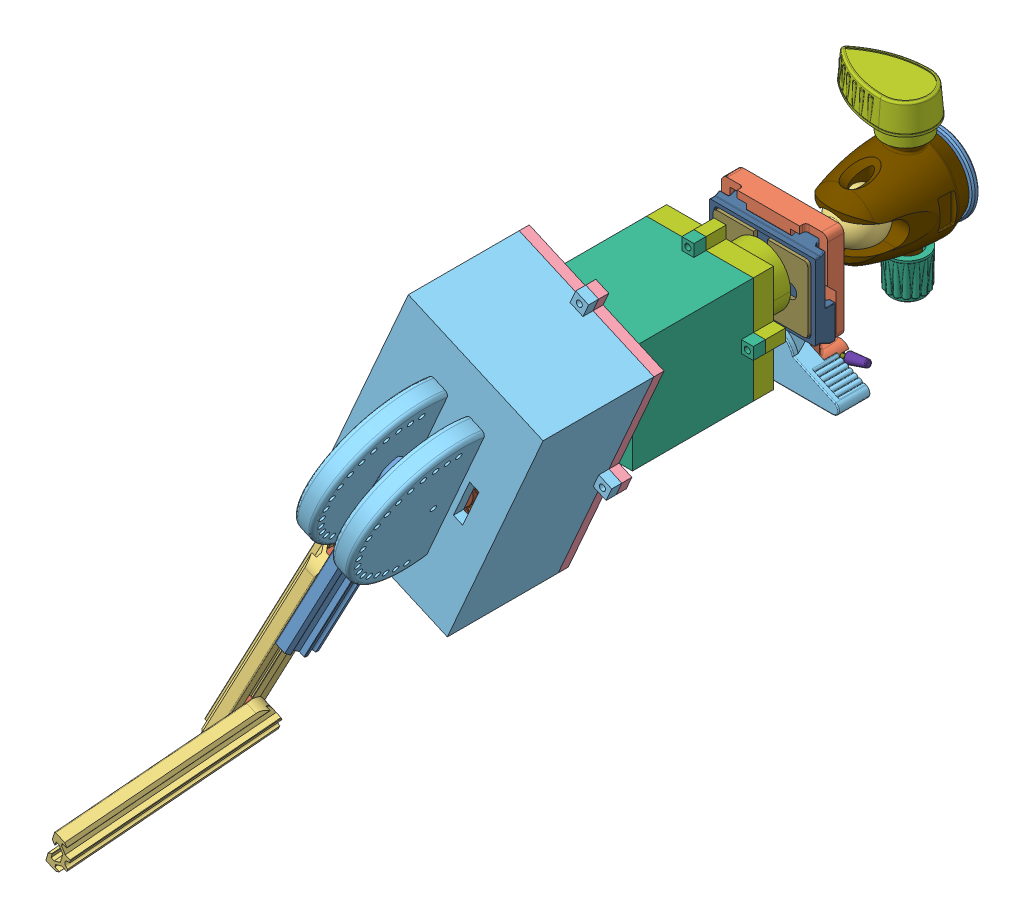
SolidWorks assembly Ensamblaje_modelo1, configuration Predeterminado. Lengths in mm.
Overall size (138.43 225.18 378.64).
164 component instances, 151 part files, 39 mates.
Components (placement in the parent):
- Brazo_10cm_aluminnino-1: Brazo_10cm_aluminnino [Predeterminado] at (-448.8005 -805.3039 -5.9199) x (0.069335 0.157727 0.985046) z (-0.915454 0.402424 0) size (20 100 10.12)
- Deslizador-3: Deslizador [Predeterminado] at (-316.6339 -504.6447 -43.0612) x (0.069335 0.157727 0.985046) z (0.396406 0.901764 -0.172294) size (11 6.1 10)
- Brazo2_10cm_aluminnino-3: Brazo2_10cm_aluminnino [Predeterminado] at (-469.25 -851.8237 23.2719) x (-0.069335 -0.157727 -0.985046) z (0.915454 -0.402424 0) size (20 100 10.12)
- Deslizador-4: Deslizador [Predeterminado] at (-312.6698 -495.6271 -44.7841) x (0.069335 0.157727 0.985046) z (-0.396406 -0.901764 0.172294) size (11 6.1 10)
- Deslizador-5: Deslizador [Predeterminado] at (-349.733 -579.9403 -48.9786) x (-0.069335 -0.157727 -0.985046) z (0.396406 0.901764 -0.172294) size (11 6.1 10)
- Brazo2_10cm_aluminnino-4: Brazo2_10cm_aluminnino [Predeterminado] at (-378.3724 -645.0906 342.2993) x (0.396265 0.901444 0.174278) z (-0.915454 0.402424 0) size (20 100 10.12)
- Deslizador-6: Deslizador [Predeterminado] at (-350.6696 -582.071 -46.6558) x (-0.396265 -0.901444 -0.174278) z (-0.070134 -0.159543 0.984696) size (11 6.1 10)
- Base_electronica-1: Base_electronica [Predeterminado] at (-294.7034 -471.5152 -134.264) x (0.402424 0.915454 0) z (0 0 -1) size (132 87 23)
- Carcaza_electronica-2: Carcaza_electronica [Predeterminado] at (-297.1955 -448.8025 -29.264) x (-0.402424 -0.915454 0) z (0 0 -1) size (132 87 104.68)
- Soporte_motor_superior-1: Soporte_motor_superior [Predeterminado] at (-288.9316 -454.051 -209.264) size (65 65 60)
- motor_abajo_acople-1: motor_abajo_acople [Predeterminado] at (-288.9316 -454.051 -209.264) x (0 1 0) z (0 0 -1) size (65 65 30)
- Manfrotto - 494RC2 Head Assy-1: Manfrotto - 494RC2 Head Assy [Predeterminado] at (-288.9316 -453.3297 -286.264) x (0 1 0) z (1 0 0) size (91.96 94.5 69.28)
  - Manfrotto - 494RC2 Head Assy.stp-1: Manfrotto - 494RC2 Head Assy.stp [Predeterminado] at origin size (91.96 94.5 69.28)
    - Quick Release Assy.stp-1: Quick Release Assy.stp [Predeterminado] at (-0.7213 41 0) x (-1 0 0) z (0 0 -1) size (42.4 16.85 52.52)
      - Thumb Screw Assy.stp-1: Thumb Screw Assy.stp [Predeterminado] at (0 -1.5 0) x (0 0 -1) z (-1 0 0) size (29.5 16 20.75)
        - Thumb Screw.stp-1: Thumb Screw.stp [Predeterminado] at origin size (15.01 16 15)
        - Thumb Screw Handle.stp-1: Thumb Screw Handle.stp [Predeterminado] at (0 1 0) size (29.5 2.5 14.5)
      - Quick Release Mounting.stp-1: Quick Release Mounting.stp [Predeterminado] at origin size (42.4 10.35 52.52)
      - IS 3075-3 3.2.stp-1: IS 3075-3 3.2.stp [Predeterminado] at (0 3.5 -1.9764) x (1 0 0) z (0 1 0) size (7.3 6.15 0.6)
      - Quick Release Rubber Pad.stp-1: Quick Release Rubber Pad.stp [Predeterminado] at (0 5 0) x (-1 0 0) z (0 0 -1) size (33 2 47)
    - Manfrotto Logo 01.stp-1: Manfrotto Logo 01.stp [Predeterminado] at (0 -22 -19) x (-1 0 0) z (0 -1 0) size (8.5 1.8 8.5)
      - Manfrotto Logo 01 - 1.stp-1: Manfrotto Logo 01 - 1.stp [Predeterminado] at origin size (8.5 0.3 8.5)
      - Manfrotto Logo 01 - 2.stp-1: Manfrotto Logo 01 - 2.stp [Predeterminado] at (0 1.05 0) x (0 0 1) z (-1 0 0) size (8.5 1.5 8.5)
    - Locking Pin Assy.stp-1: Locking Pin Assy.stp [Predeterminado] at (-40.5 28.5 12.6) x (0.97437 0 -0.224951) z (0.224951 0 0.97437) size (7 17 21)
      - Locking Pin.stp-1: Locking Pin.stp [Predeterminado] at origin size (7 17 7)
      - Locking Pin Lever.stp-1: Locking Pin Lever.stp [Predeterminado] at (0 -5.5 6) x (1 0 0) z (0 1 0) size (2 17 2)
      - Locking Pin Lever Rubber.stp-1: Locking Pin Lever Rubber.stp [Predeterminado] at (0 -5.5 12.5) size (4.96 4.96 10)
    - Base Casting.stp-1: Base Casting.stp [Predeterminado] at origin size (64 51.03 43.02)
    - Base Plate.stp-1: Base Plate.stp [Predeterminado] at (0 -40.5 0) size (39.5 19 39.5)
    - Mount Casting.stp-1: Mount Casting.stp [Predeterminado] at (0 36 0) size (71.96 24.08 53.67)
    - Ball Joint.stp-1: Ball Joint.stp [Predeterminado] at (0 -1 0) size (25 40.5 25)
    - ISO 10642 M5 x  16.stp-1: ISO 10642 M5 x  16.stp [Predeterminado] at (0 34.6 0) x (0 -1 0) z (0 0 1) size (16 9.43 9.43)
    - Quick Release Catch.stp-1: Quick Release Catch.stp [Predeterminado] at (-34 40.5 -0.9) size (25 15.5 49)
    - Friction Knob.stp-1: Friction Knob.stp [Predeterminado] at (-25 -26 0) x (0 1 0) z (0 0 1) size (19.07 19 19.04)
    - Locking Knob.stp-1: Locking Knob.stp [Predeterminado] at (31.5 -25 0) x (0 1 0) z (0 0 -1) size (27.31 20.5 46)
- NEMA17 17HS8401.step-4: NEMA17 17HS8401.step [Predeterminado] at (-288.9316 -454.051 -154.264) x (-1 0 0) z (0 -1 0) size (42 72.35 47.08)
- Raspberry-1: Raspberry [Predeterminado] at (-301.1009 -413.7462 -103.764) x (-0.402424 -0.915454 0) z (0 0 1) size (88 57 24.1)
  - full raspberry pi 4 upgrade cooling.step-1: full raspberry pi 4 upgrade cooling.step [Predeterminado] at origin size (88 57 24.1)
    - радиатор верх.step-1: радиатор верх.step [Predeterminado] at (70 0 7.1) size (70 56 15)
    - радиатор низ.step-1: радиатор низ.step [Predeterminado] at (0 0 -2.5) x (0 1 0) z (0 0 -1) size (56 87 7.5)
    - вентилятор.step-1: вентилятор.step [Predeterminado] at (46.1053 34.1447 9.6) x (0 -1 0) z (0 0 -1) size (25 25 6)
    - вентилятор.step-2: вентилятор.step [Predeterminado] at (21.1053 34.1447 9.6) x (0 -1 0) z (0 0 -1) size (25 25 6)
    - распбери 4.step-1: распбери 4.step [Predeterminado] at origin size (85 56 1.6)
    - распбери 4-0.step-1: распбери 4-0.step [Predeterminado] at origin size (2.5 5 2.4)
    - распбери 4-1.step-1: распбери 4-1.step [Predeterminado] at origin size (2.5 5 2.4)
    - распбери 4-2.step-1: распбери 4-2.step [Predeterminado] at origin size (2.5 5 2.4)
    - распбери 4-3.step-1: распбери 4-3.step [Predeterminado] at origin size (2.5 5 2.4)
    - распбери 4-4.step-1: распбери 4-4.step [Predeterminado] at origin size (2.5 5 2.4)
    - распбери 4-5.step-1: распбери 4-5.step [Predeterminado] at origin size (2.5 5 2.4)
    - распбери 4-6.step-1: распбери 4-6.step [Predeterminado] at origin size (2.5 5 2.4)
    - распбери 4-7.step-1: распбери 4-7.step [Predeterminado] at origin size (2.5 5 2.4)
    - распбери 4-8.step-1: распбери 4-8.step [Predeterminado] at origin size (2.5 5 2.4)
    - распбери 4-9.step-1: распбери 4-9.step [Predeterminado] at origin size (2.5 5 2.4)
    - распбери 4-10.step-1: распбери 4-10.step [Predeterminado] at origin size (2.5 5 2.4)
    - распбери 4-11.step-1: распбери 4-11.step [Predeterminado] at origin size (2.5 5 2.4)
    - распбери 4-12.step-1: распбери 4-12.step [Predeterminado] at origin size (2.5 5 2.4)
    - распбери 4-13.step-1: распбери 4-13.step [Predeterminado] at origin size (2.5 5 2.4)
    - распбери 4-14.step-1: распбери 4-14.step [Predeterminado] at origin size (2.5 5 2.4)
    - распбери 4-15.step-1: распбери 4-15.step [Predeterminado] at origin size (2.5 5 2.4)
    - распбери 4-16.step-1: распбери 4-16.step [Predeterminado] at origin size (2.5 5 2.4)
    - распбери 4-17.step-1: распбери 4-17.step [Predeterminado] at origin size (2.5 5 2.4)
    - распбери 4-18.step-1: распбери 4-18.step [Predeterminado] at origin size (2.5 5 2.4)
    - распбери 4-19.step-1: распбери 4-19.step [Predeterminado] at origin size (2.5 5 2.4)
    - распбери 4-20.step-1: распбери 4-20.step [Predeterminado] at origin size (2.5 2.5 2.4)
    - распбери 4-21.step-1: распбери 4-21.step [Predeterminado] at origin size (2.5 2.5 2.4)
    - распбери 4-22.step-1: распбери 4-22.step [Predeterminado] at origin size (2.5 2.5 2.4)
    - распбери 4-23.step-1: распбери 4-23.step [Predeterminado] at origin size (2.5 2.5 2.4)
    - распбери 4-24.step-1: распбери 4-24.step [Predeterminado] at origin size (0.65 0.65 11.5)
    - распбери 4-25.step-1: распбери 4-25.step [Predeterminado] at origin size (0.65 0.65 11.5)
    - распбери 4-26.step-1: распбери 4-26.step [Predeterminado] at origin size (0.65 0.65 11.5)
    - распбери 4-27.step-1: распбери 4-27.step [Predeterminado] at origin size (0.65 0.65 11.5)
    - распбери 4-28.step-1: распбери 4-28.step [Predeterminado] at origin size (0.65 0.65 11.5)
    - распбери 4-29.step-1: распбери 4-29.step [Predeterminado] at origin size (0.65 0.65 11.5)
    - распбери 4-30.step-1: распбери 4-30.step [Predeterminado] at origin size (0.65 0.65 11.5)
    - распбери 4-31.step-1: распбери 4-31.step [Predeterminado] at origin size (0.65 0.65 11.5)
    - распбери 4-32.step-1: распбери 4-32.step [Predeterminado] at origin size (0.65 0.65 11.5)
    - распбери 4-33.step-1: распбери 4-33.step [Predeterminado] at origin size (0.65 0.65 11.5)
    - распбери 4-34.step-1: распбери 4-34.step [Predeterminado] at origin size (0.65 0.65 11.5)
    - распбери 4-35.step-1: распбери 4-35.step [Predeterminado] at origin size (0.65 0.65 11.5)
    - распбери 4-36.step-1: распбери 4-36.step [Predeterminado] at origin size (0.65 0.65 11.5)
    - распбери 4-37.step-1: распбери 4-37.step [Predeterminado] at origin size (0.65 0.65 11.5)
    - распбери 4-38.step-1: распбери 4-38.step [Predeterminado] at origin size (0.65 0.65 11.5)
    - распбери 4-39.step-1: распбери 4-39.step [Predeterminado] at origin size (0.65 0.65 11.5)
    - распбери 4-40.step-1: распбери 4-40.step [Predeterminado] at origin size (0.65 0.65 11.5)
    - распбери 4-41.step-1: распбери 4-41.step [Predeterminado] at origin size (0.65 0.65 11.5)
    - распбери 4-42.step-1: распбери 4-42.step [Predeterminado] at origin size (0.65 0.65 11.5)
    - распбери 4-43.step-1: распбери 4-43.step [Predeterminado] at origin size (0.65 0.65 11.5)
    - распбери 4-44.step-1: распбери 4-44.step [Predeterminado] at origin size (0.65 0.65 11.5)
    - распбери 4-45.step-1: распбери 4-45.step [Predeterminado] at origin size (0.65 0.65 11.5)
    - распбери 4-46.step-1: распбери 4-46.step [Predeterminado] at origin size (0.65 0.65 11.5)
    - распбери 4-47.step-1: распбери 4-47.step [Predeterminado] at origin size (0.65 0.65 11.5)
    - распбери 4-48.step-1: распбери 4-48.step [Predeterminado] at origin size (0.65 0.65 11.5)
    - распбери 4-49.step-1: распбери 4-49.step [Predeterminado] at origin size (0.65 0.65 11.5)
    - распбери 4-50.step-1: распбери 4-50.step [Predeterminado] at origin size (0.65 0.65 11.5)
    - распбери 4-51.step-1: распбери 4-51.step [Predeterminado] at origin size (0.65 0.65 11.5)
    - распбери 4-52.step-1: распбери 4-52.step [Predeterminado] at origin size (0.65 0.65 11.5)
    - распбери 4-53.step-1: распбери 4-53.step [Predeterminado] at origin size (0.65 0.65 11.5)
    - распбери 4-54.step-1: распбери 4-54.step [Predeterminado] at origin size (0.65 0.65 11.5)
    - распбери 4-55.step-1: распбери 4-55.step [Predeterminado] at origin size (0.65 0.65 11.5)
    - распбери 4-56.step-1: распбери 4-56.step [Predeterminado] at origin size (0.65 0.65 11.5)
    - распбери 4-57.step-1: распбери 4-57.step [Predeterminado] at origin size (0.65 0.65 11.5)
    - распбери 4-58.step-1: распбери 4-58.step [Predeterminado] at origin size (0.65 0.65 11.5)
    - распбери 4-59.step-1: распбери 4-59.step [Predeterminado] at origin size (0.65 0.65 11.5)
    - распбери 4-60.step-1: распбери 4-60.step [Predeterminado] at origin size (0.65 0.65 11.5)
    - распбери 4-61.step-1: распбери 4-61.step [Predeterminado] at origin size (0.65 0.65 11.5)
    - распбери 4-62.step-1: распбери 4-62.step [Predeterminado] at origin size (0.65 0.65 11.5)
    - распбери 4-63.step-1: распбери 4-63.step [Predeterminado] at origin size (0.65 0.65 11.5)
    - распбери 4-64.step-1: распбери 4-64.step [Predeterminado] at origin size (0.65 0.65 11.5)
    - распбери 4-65.step-1: распбери 4-65.step [Predeterminado] at origin size (0.65 0.65 11.5)
    - распбери 4-66.step-1: распбери 4-66.step [Predeterminado] at origin size (0.65 0.65 11.5)
    - распбери 4-67.step-1: распбери 4-67.step [Predeterminado] at origin size (0.65 0.65 11.5)
    - распбери 4-68.step-1: распбери 4-68.step [Predeterminado] at origin size (0.8 14 5)
    - распбери 4-69.step-1: распбери 4-69.step [Predeterminado] at origin size (2.5 20 5)
    - распбери 4-70.step-1: распбери 4-70.step [Predeterminado] at origin size (2.5 20 5)
    - распбери 4-71.step-1: распбери 4-71.step [Predeterminado] at origin size (0.8 14 5)
    - распбери 4-72.step-1: распбери 4-72.step [Predeterminado] at origin size (11 13 2)
    - распбери 4-73.step-1: распбери 4-73.step [Predeterminado] at origin size (15 15 2.5)
    - распбери 4-74.step-1: распбери 4-74.step [Predeterminado] at origin size (10 15 1)
    - распбери 4-75.step-1: распбери 4-75.step [Predeterminado] at origin size (8 8 1)
    - распбери 4-76.step-1: распбери 4-76.step [Predeterminado] at origin size (6 6 1)
    - распбери 4-77.step-1: распбери 4-77.step [Predeterminado] at origin size (4.5 7 2)
    - распбери 4-78.step-1: распбери 4-78.step [Predeterminado] at origin size (9 7 3)
    - распбери 4-79.step-1: распбери 4-79.step [Predeterminado] at origin size (6.5 7 3)
    - распбери 4-80.step-1: распбери 4-80.step [Predeterminado] at origin size (6.5 7 3)
    - распбери 4-81.step-1: распбери 4-81.step [Predeterminado] at origin size (6.5 0.5 3)
    - распбери 4-82.step-1: распбери 4-82.step [Predeterminado] at origin size (7 12.5 6)
    - распбери 4-83.step-1: распбери 4-83.step [Predeterminado] at origin size (6 1 6)
    - распбери 4-84.step-1: распбери 4-84.step [Predeterminado] at origin size (18 13 15)
    - распбери 4-85.step-1: распбери 4-85.step [Predeterminado] at origin size (9 10 1)
    - распбери 4-86.step-1: распбери 4-86.step [Predeterminado] at origin size (9 10 1)
    - распбери 4-87.step-1: распбери 4-87.step [Predeterminado] at origin size (9 10 1)
    - распбери 4-88.step-1: распбери 4-88.step [Predeterminado] at origin size (9 12 9.5)
    - распбери 4-89.step-1: распбери 4-89.step [Predeterminado] at origin size (9 10 1)
    - распбери 4-90.step-1: распбери 4-90.step [Predeterminado] at origin size (3 2.6 1.5)
    - распбери 4-91.step-1: распбери 4-91.step [Predeterminado] at origin size (3 2.6 1.5)
    - распбери 4-92.step-1: распбери 4-92.step [Predeterminado] at origin size (6 2.6 1.5)
    - распбери 4-93.step-1: распбери 4-93.step [Predeterminado] at origin size (6 2.6 1.5)
    - распбери 4-94.step-1: распбери 4-94.step [Predeterminado] at origin size (18 16 13.5)
    - распбери 4-95.step-1: распбери 4-95.step [Predeterminado] at origin size (8 12.2 5.1)
    - распбери 4-96.step-1: распбери 4-96.step [Predeterminado] at origin size (7 1.2 0.6)
    - распбери 4-97.step-1: распбери 4-97.step [Predeterminado] at origin size (7 1.2 0.6)
    - распбери 4-98.step-1: распбери 4-98.step [Predeterminado] at origin size (7 1.2 0.6)
    - распбери 4-99.step-1: распбери 4-99.step [Predeterminado] at origin size (7 1.2 0.6)
    - распбери 4-100.step-1: распбери 4-100.step [Predeterminado] at origin size (7 1.2 0.6)
    - распбери 4-101.step-1: распбери 4-101.step [Predeterminado] at origin size (7 1.2 0.6)
    - распбери 4-102.step-1: распбери 4-102.step [Predeterminado] at origin size (7 1.2 0.6)
    - распбери 4-103.step-1: распбери 4-103.step [Predeterminado] at origin size (7 1.2 0.6)
    - распбери 4-104.step-1: распбери 4-104.step [Predeterminado] at origin size (7 1.2 0.6)
    - распбери 4-105.step-1: распбери 4-105.step [Predeterminado] at origin size (7 1.2 0.6)
    - распбери 4-106.step-1: распбери 4-106.step [Predeterminado] at origin size (7 1.2 0.6)
    - распбери 4-107.step-1: распбери 4-107.step [Predeterminado] at origin size (18 13 15)
    - распбери 4-108.step-1: распбери 4-108.step [Predeterminado] at origin size (7 1.2 0.6)
    - распбери 4-109.step-1: распбери 4-109.step [Predeterminado] at origin size (13 11 1)
    - распбери 4-110.step-1: распбери 4-110.step [Predeterminado] at origin size (13 11 1)
    - распбери 4-111.step-1: распбери 4-111.step [Predeterminado] at origin size (7 0.6 0.2)
    - распбери 4-112.step-1: распбери 4-112.step [Predeterminado] at origin size (7 0.6 0.2)
    - распбери 4-113.step-1: распбери 4-113.step [Predeterminado] at origin size (7 0.6 0.2)
    - распбери 4-114.step-1: распбери 4-114.step [Predeterminado] at origin size (7 0.6 0.2)
    - распбери 4-115.step-1: распбери 4-115.step [Predeterminado] at origin size (7 0.6 0.2)
    - распбери 4-116.step-1: распбери 4-116.step [Predeterminado] at origin size (7 0.6 0.2)
    - распбери 4-117.step-1: распбери 4-117.step [Predeterminado] at origin size (7 0.6 0.2)
    - распбери 4-118.step-1: распбери 4-118.step [Predeterminado] at origin size (7 0.6 0.2)
    - распбери 4-119.step-1: распбери 4-119.step [Predeterminado] at origin size (8.63 10.92 0.05)
    - распбери 4-120.step-1: распбери 4-120.step [Predeterminado] at origin size (11 12 1.4)
Mates (geometry in assembly coordinates):
- Coincidente29: coincident anti-aligned: plane of Brazo_10cm_aluminnino-1 through (-288.279 -444.6129 -70.4047) normal (0.069335 0.157727 0.985046); plane of Deslizador-3 through (-310.5959 -499.4559 -60.0523) normal (-0.069335 -0.157727 -0.985046)
- Coincidente31: coincident anti-aligned: plane of Brazo_10cm_aluminnino-1 through (-283.9438 -445.4364 -64.7407) normal (-0.915454 0.402424 0); plane of Deslizador-3 through (-307.7622 -499.6194 -54.3883) normal (0.915454 -0.402424 0)
- Coincidente33: coincident anti-aligned: plane of Brazo_10cm_aluminnino-1 through (-289.8624 -443.7437 -69.4985) normal (-0.915454 0.402424 0); plane of Brazo2_10cm_aluminnino-3 through (-311.6987 -493.4179 -60.0075) normal (0.915454 -0.402424 0)
- Coincidente34: coincident aligned: plane of Brazo_10cm_aluminnino-1 through (-285.2764 -446.7797 -74.8374) normal (-0.069335 -0.157727 -0.985046); plane of Brazo2_10cm_aluminnino-3 through (-317.0362 -492.0917 -65.3465) normal (-0.069335 -0.157727 -0.985046)
- Coincidente35: coincident anti-aligned: plane of Brazo2_10cm_aluminnino-3 through (-316.9821 -490.2804 -55.7423) normal (0.915454 -0.402424 0); plane of Deslizador-4 through (-322.8935 -503.728 -52.6654) normal (-0.915454 0.402424 0)
- Coincidente36: coincident anti-aligned: plane of Brazo2_10cm_aluminnino-3 through (-314.911 -492.179 -60.9138) normal (0.069335 0.157727 0.985046); plane of Deslizador-4 through (-320.8571 -505.7054 -58.3294) normal (-0.069335 -0.157727 -0.985046)
- Concéntrica10: concentric aligned: cylinder of Brazo2_10cm_aluminnino-3 through (-330.0834 -495.2344 -53.7731) axis (0.915454 -0.402424 0) radius 1.5; cylinder of Deslizador-4 through (-320.9288 -499.2586 -53.7731) axis (0.915454 -0.402424 0) radius 1.5
- Concéntrica11: concentric anti-aligned: cylinder of Deslizador-3 through (-309.7615 -504.1677 -53.7731) axis (-0.915454 0.402424 0) radius 1.5; cylinder of Deslizador-4 through (-320.9288 -499.2586 -53.7731) axis (0.915454 -0.402424 0) radius 1.5
- Coincidente37: coincident anti-aligned: plane of Brazo2_10cm_aluminnino-3 through (-316.9821 -490.2804 -55.7423) normal (0.915454 -0.402424 0); plane of Deslizador-5 through (-350.6766 -566.9303 -41.0973) normal (-0.915454 0.402424 0)
- Coincidente39: coincident anti-aligned: plane of Brazo2_10cm_aluminnino-3 through (-314.911 -492.179 -60.9138) normal (0.069335 0.157727 0.985046); plane of Deslizador-5 through (-347.1042 -569.4888 -46.2688) normal (-0.069335 -0.157727 -0.985046)
- Concéntrica13: concentric aligned: cylinder of Brazo2_10cm_aluminnino-3 through (-361.482 -567.5134 -39.9896) axis (0.915454 -0.402424 0) radius 1.5; cylinder of Deslizador-5 through (-352.6413 -571.3997 -39.9896) axis (0.915454 -0.402424 0) radius 1.5
- Coincidente40: coincident anti-aligned: plane of Brazo2_10cm_aluminnino-3 through (-311.6987 -493.4179 -60.0075) normal (0.915454 -0.402424 0); plane of Brazo2_10cm_aluminnino-4 through (-348.1712 -576.3874 -50.6347) normal (-0.915454 0.402424 0)
- Coincidente41: coincident anti-aligned: plane of Brazo2_10cm_aluminnino-4 through (-341.0283 -568.6849 -48.878) normal (-0.396265 -0.901444 -0.174278); plane of Deslizador-6 through (-342.0803 -571.0781 -34.1076) normal (0.396265 0.901444 0.174278)
- Coincidente42: coincident anti-aligned: plane of Brazo2_10cm_aluminnino-4 through (-340.6736 -574.488 -49.793) normal (-0.915454 0.402424 0); plane of Deslizador-6 through (-341.9237 -577.3318 -35.1097) normal (0.915454 -0.402424 0)
- Concéntrica14: concentric aligned: cylinder of Brazo2_10cm_aluminnino-4 through (-332.3194 -580.333 -39.9896) axis (-0.915454 0.402424 0) radius 1.5; cylinder of Deslizador-6 through (-341.474 -576.3088 -39.9896) axis (-0.915454 0.402424 0) radius 1.5
- Concéntrica15: concentric anti-aligned: cylinder of Brazo2_10cm_aluminnino-3 through (-361.482 -567.5134 -39.9896) axis (0.915454 -0.402424 0) radius 1.5; cylinder of Deslizador-6 through (-341.474 -576.3088 -39.9896) axis (-0.915454 0.402424 0) radius 1.5
- Distancia límite1: limit distance = 29.9143 mm aligned: plane of Deslizador-3 through (-316.6339 -504.6447 -43.0612) normal (-0.396406 -0.901764 0.172294); plane of Brazo_10cm_aluminnino-1 through (-329.8788 -534.7749 -57.608) normal (-0.396406 -0.901764 0.172294)
- Concéntrica52: concentric anti-aligned: cylinder of Brazo_10cm_aluminnino-1 through (-293.5089 -452.0389 -63.264) axis (0.915454 -0.402424 0) radius 1.5; cylinder of Carcaza_electronica-2 through (-275.1998 -460.0874 -63.264) axis (-0.915454 0.402424 0) radius 1.5
- Coincidente80: coincident anti-aligned: plane of Brazo_10cm_aluminnino-1 through (-289.8624 -443.7437 -69.4985) normal (-0.915454 0.402424 0); plane of Carcaza_electronica-2 through (-293.5089 -452.0389 -63.264) normal (0.915454 -0.402424 0)
- Ángulo límite1: limit planar angle = 0.173158 rad aligned: plane of Brazo_10cm_aluminnino-1 through (-283.8897 -443.6251 -55.1365) normal (0.069335 0.157727 0.985046); plane of Carcaza_electronica-2 through (-298.6027 -385.3508 -74.264) normal (0 0 1)
- Coincidente82: coincident anti-aligned: plane of Raspberry Pi 4 single-board controller.step-2/2X USB3.0 PORTS, RPi4ModelB.step-1 through (-305.012 -399.0171 -101.564) normal (0 0 1); plane of Carcaza_electronica-2 through (-332.8064 -487.8842 -85.464) normal (0 0 -1)
- Coincidente83: coincident anti-aligned: plane of Raspberry Pi 4 single-board controller.step-2/Gigabit Ethernet Port, RPi4ModelB.step-1 through (-325.1457 -402.5998 -117.064) normal (-0.984534 -0.175195 0); plane of Carcaza_electronica-2 through (-284.1134 -509.2891 -101.164) normal (-0.915454 0.402424 0)
- Distancia3: distance = 5 mm aligned: plane of Raspberry Pi 4 single-board controller.step-2/PCB, RPi4ModelB.step-1 through (-326.8846 -405.9564 -117.064) normal (-0.175195 0.984534 0); plane of Carcaza_electronica-2 through (-346.0887 -493.3743 -129.264) normal (-0.402424 -0.915454 0)
- Coincidente85: coincident anti-aligned: plane of Soporte_motor_superior-1 through (-288.9316 -454.051 -209.264) normal (0 0 -1); plane of motor_abajo_acople-1 through (-288.9316 -454.051 -209.264) normal (0 0 1)
- Coincidente86: coincident aligned: plane of Soporte_motor_superior-1 through (-315.4316 -427.551 -209.264) normal (-1 0 0); plane of motor_abajo_acople-1 through (-315.4316 -480.551 -209.264) normal (-1 0 0)
- Coincidente87: coincident aligned: plane of Soporte_motor_superior-1 through (-262.4316 -427.551 -209.264) normal (0 1 0); plane of motor_abajo_acople-1 through (-315.4316 -427.551 -209.264) normal (0 1 0)
- Concéntrica54: concentric anti-aligned: cylinder of motor_abajo_acople-1 through (-288.9316 -454.051 -229.264) axis (0 0 -1) radius 6; cylinder of Manfrotto - 494RC2 Head Assy-1/Manfrotto - 494RC2 Head Assy.stp-1/Quick Release Assy.stp-1/Thumb Screw Assy.stp-1/Thumb Screw.stp-1 through (-288.9316 -454.051 -237.764) axis (0 0 1) radius 3
- Coincidente89: coincident anti-aligned: plane of motor_abajo_acople-1 through (-288.9316 -454.051 -239.264) normal (0 0 -1); plane of Manfrotto - 494RC2 Head Assy-1/Manfrotto - 494RC2 Head Assy.stp-1/Quick Release Assy.stp-1/Quick Release Rubber Pad.stp-1 through (-288.9316 -454.051 -239.264) normal (0 0 1)
- Distancia4: distance = 15 mm anti-aligned: plane of Base_electronica-1 through (-294.7034 -471.5152 -134.264) normal (0 0 -1); plane of Soporte_motor_superior-1 through (-288.9316 -454.051 -149.264) normal (0 0 1)
- Concéntrica56: concentric aligned: cylinder of Soporte_motor_superior-1 through (-304.4316 -438.551 -149.264) axis (0 0 -1) radius 1.5; cylinder of NEMA17 17HS8401.step-4 through (-304.4316 -438.551 -154.264) axis (0 0 -1) radius 1.2295
- Concéntrica57: concentric aligned: cylinder of Soporte_motor_superior-1 through (-288.9316 -454.051 -149.264) axis (0 0 -1) radius 11.05; cylinder of NEMA17 17HS8401.step-4 through (-288.9316 -454.051 -152.264) axis (0 0 -1) radius 11
- Coincidente91: coincident anti-aligned: plane of Soporte_motor_superior-1 through (-288.9316 -454.051 -154.264) normal (0 0 -1); plane of NEMA17 17HS8401.step-4 through (-288.9316 -454.051 -154.264) normal (0 0 1)
- Concéntrica58: concentric anti-aligned: cylinder of Base_electronica-1 through (-288.9316 -454.051 -139.264) axis (0 0 1) radius 11; cylinder of NEMA17 17HS8401.step-4 through (-288.9316 -454.051 -129.912) axis (0 0 -1) radius 2.5
- Coincidente93: coincident anti-aligned: plane of Base_electronica-1 through (-294.7034 -471.5152 -129.264) normal (0 0 1); plane of Carcaza_electronica-2 through (-297.1955 -448.8025 -129.264) normal (0 0 -1)
- Coincidente94: coincident aligned: plane of Base_electronica-1 through (-320.9372 -436.1585 -129.264) normal (-0.915454 0.402424 0); plane of Carcaza_electronica-2 through (-298.6027 -385.3508 -129.264) normal (-0.915454 0.402424 0)
- Coincidente95: coincident aligned: plane of Base_electronica-1 through (-315.8787 -506.6543 -129.264) normal (-0.402424 -0.915454 0); plane of Carcaza_electronica-2 through (-346.0887 -493.3743 -129.264) normal (-0.402424 -0.915454 0)
- Coincidente96: coincident anti-aligned: plane of Base_electronica-1 through (-294.7034 -471.5152 -111.264) normal (0 0 1); plane of Raspberry-1/full raspberry pi 4 upgrade cooling.step-1/радиатор низ.step-1 through (-292.9736 -464.8363 -111.264) normal (0 0 -1)
- Distancia5: distance = 1 mm anti-aligned: plane of Carcaza_electronica-2 through (-284.1134 -509.2891 -101.164) normal (-0.915454 0.402424 0); plane of Raspberry-1/full raspberry pi 4 upgrade cooling.step-1/распбери 4-94.step-1 through (-286.7879 -512.8882 -102.164) normal (0.915454 -0.402424 0)
- Distancia6: distance = 1 mm anti-aligned: plane of Carcaza_electronica-2 through (-340.8172 -491.3222 -43.264) normal (0.402424 0.915454 0); plane of Raspberry-1/full raspberry pi 4 upgrade cooling.step-1/распбери 4-94.step-1 through (-295.3188 -512.4152 -95.414) normal (-0.402424 -0.915454 0)
